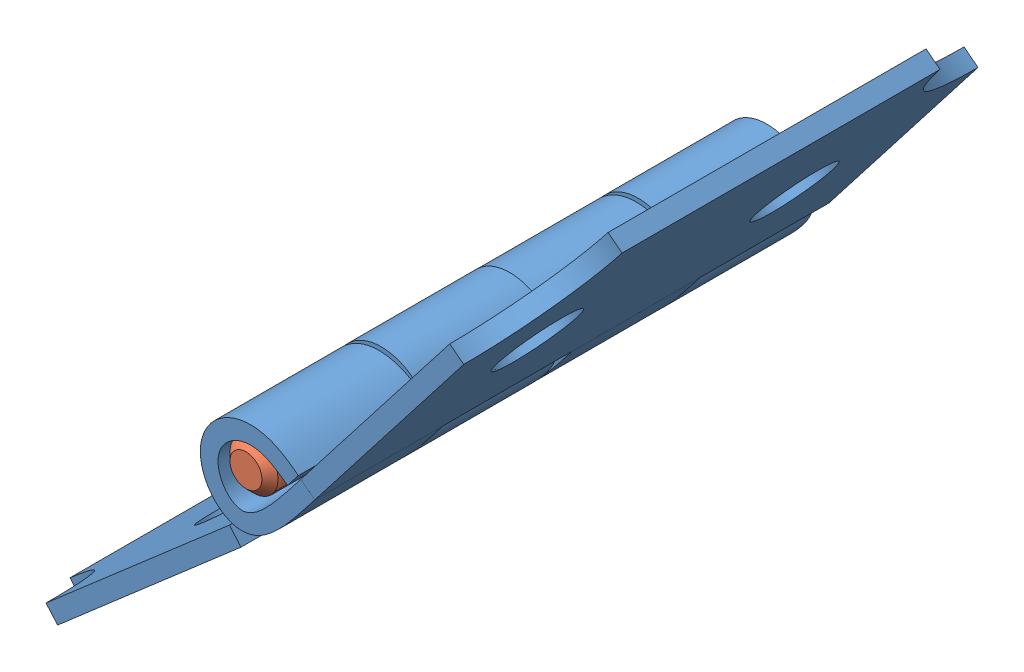
SolidWorks assembly Hinge-V1816-National-N211-441, configuration Default. Lengths in mm.
Overall size (18.77 19.58 16.01).
3 component instances, 2 part files, 4 mates.
Components (placement in the parent):
- HingeSide-1: HingeSide [Default] at (0.9994 -1.1519 8) x (0.755322 0.655354 -0.00006) z (0.000045 0.000039 1) size (13.95 2.98 16)
- HingeSide-2: HingeSide [Default] at (1.2045 -0.9354 8) x (-0.613383 -0.789786 0.00006) z (-0.000037 -0.000047 -1) size (13.95 2.98 16)
- Spindle-1: Spindle [Default] at origin size (1.5 1.5 16)
Mates (geometry in assembly coordinates):
- Concentric4: concentric aligned: circle of HingeSide-2; cylinder of Spindle-1 through (0 0 16) axis (0 0 -1) radius 0.75
- Coincident14: coincident aligned: plane of HingeSide-2 through (0.7701 -0.598 16) normal (0 0 1); plane of Spindle-1 through (0 0 16) normal (0 0 1)
- Concentric5: concentric anti-aligned: circle of HingeSide-1; cylinder of Spindle-1 through (0 0 16) axis (0 0 -1) radius 0.75
- Coincident15: coincident aligned: plane of HingeSide-1 through (0.6389 -0.7365 0) normal (0 0 -1); plane of Spindle-1 through (0 0 0) normal (0 0 -1)
